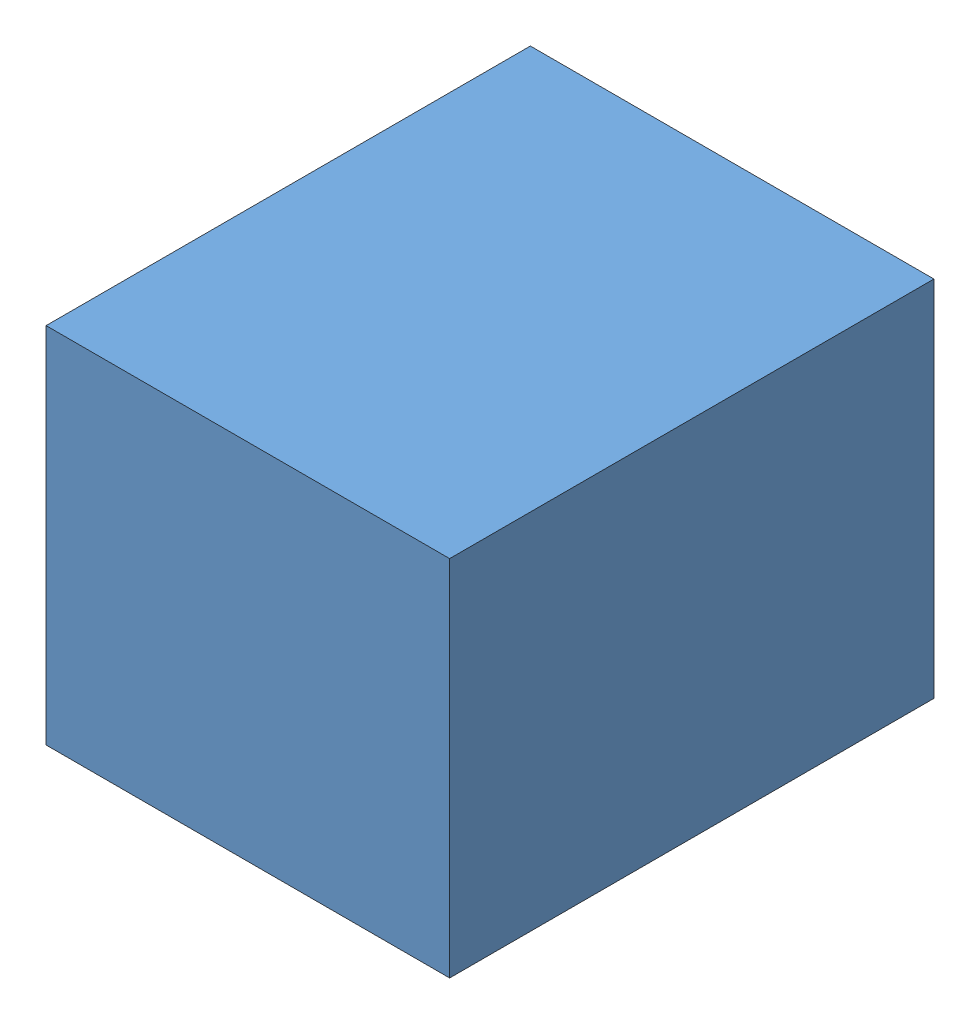
SolidWorks assembly StorageBox, configuration Default. Lengths in mm.
Overall size (500 450 600).
30 component instances, 4 part files, 20 mates.
Components (placement in the parent):
- BaseBlock-1: BaseBlock [Default] at (-55.9599 101.6948 767.1143) size (500 450 600)
- CupStorage-1: CupStorage [Default] at (882.1946 34.1249 161.3658) x (0.007369 0 0.999973) z (-0.999973 0 0.007369) size (536.8 119.37 182.42)
  - SoloCup-1: SoloCup [Default] at (135.563 292.5699 600.2365) size (96.65 119.37 96.65)
  - SoloCup-2: SoloCup [Default] at (477.5943 292.5699 516.5315) size (96.65 119.37 96.65)
  - SoloCup-3: SoloCup [Default] at (86.5797 292.5699 517.1338) size (96.65 119.37 96.65)
  - SoloCup-4: SoloCup [Default] at (429.6882 292.5699 602.3039) size (96.65 119.37 96.65)
  - SoloCup-5: SoloCup [Default] at (380.7513 292.5699 517.5282) size (96.65 119.37 96.65)
  - SoloCup-6: SoloCup [Default] at (283.0336 292.5699 517.7873) size (96.65 119.37 96.65)
  - SoloCup-7: SoloCup [Default] at (526.7308 292.5699 600.3394) size (96.65 119.37 96.65)
  - SoloCup-8: SoloCup [Default] at (234.2027 292.5699 600.9501) size (96.65 119.37 96.65)
  - SoloCup-9: SoloCup [Default] at (332.0914 292.5699 601.2137) size (96.65 119.37 96.65)
  - SoloCup-10: SoloCup [Default] at (185.2343 292.5699 517.3586) size (96.65 119.37 96.65)
  - PingPongBall-1: PingPongBall [Default] at (278.3478 273.1207 518.1565) size (38 38 38)
- CupStorage-2: CupStorage [Default] at (709.7631 34.1249 159.2975) x (0.01289 0 0.999917) z (-0.999917 0 0.01289) size (536.8 119.37 182.42)
  - SoloCup-1: SoloCup [Default] at (135.563 292.5699 600.2365) size (96.65 119.37 96.65)
  - SoloCup-2: SoloCup [Default] at (477.5943 292.5699 516.5315) size (96.65 119.37 96.65)
  - SoloCup-3: SoloCup [Default] at (86.5797 292.5699 517.1338) size (96.65 119.37 96.65)
  - SoloCup-4: SoloCup [Default] at (429.6882 292.5699 602.3039) size (96.65 119.37 96.65)
  - SoloCup-5: SoloCup [Default] at (380.7513 292.5699 517.5282) size (96.65 119.37 96.65)
  - SoloCup-6: SoloCup [Default] at (283.0336 292.5699 517.7873) size (96.65 119.37 96.65)
  - SoloCup-7: SoloCup [Default] at (526.7308 292.5699 600.3394) size (96.65 119.37 96.65)
  - SoloCup-8: SoloCup [Default] at (234.2027 292.5699 600.9501) size (96.65 119.37 96.65)
  - SoloCup-9: SoloCup [Default] at (332.0914 292.5699 601.2137) size (96.65 119.37 96.65)
  - SoloCup-10: SoloCup [Default] at (185.2343 292.5699 517.3586) size (96.65 119.37 96.65)
  - PingPongBall-1: PingPongBall [Default] at (278.3478 273.1207 518.1565) size (38 38 38)
- Battery-1: Battery [Default] at (12.3576 126.6948 331.0042) size (263 64 122)
- Battery-2: Battery [Default] at (12.3576 126.6948 465.7618) size (263 64 122)
- Battery-3: Battery [Default] at (12.3576 126.6948 605.2903) size (263 64 122)
- Battery-4: Battery [Default] at (12.3576 126.6948 733.3395) size (263 64 122)
- Battery-5: Battery [Default] at (12.3576 190.6948 540.1787) size (263 64 122)
Mates (geometry in assembly coordinates):
- Coincident11: coincident anti-aligned: plane of BaseBlock-1 through (1029.2751 326.6948 192.1143) normal (0 1 0); plane of CupStorage-1/SoloCup-1 through (282.9734 326.6948 301.3482) normal (0 -1 0)
- Coincident12: coincident anti-aligned: plane of BaseBlock-1 through (1029.2751 326.6948 192.1143) normal (0 1 0); plane of CupStorage-1/SoloCup-2 through (369.1965 326.6948 642.7535) normal (0 -1 0)
- Coincident13: coincident anti-aligned: plane of BaseBlock-1 through (1029.2751 326.6948 192.1143) normal (0 1 0); plane of CupStorage-1/SoloCup-3 through (365.7128 326.6948 251.7539) normal (0 -1 0)
- Coincident14: coincident anti-aligned: plane of BaseBlock-1 through (1029.2751 326.6948 192.1143) normal (0 1 0); plane of CupStorage-1/SoloCup-4 through (283.0734 326.6948 595.4807) normal (0 -1 0)
- Coincident15: coincident anti-aligned: plane of BaseBlock-1 through (1029.2751 326.6948 192.1143) normal (0 1 0); plane of CupStorage-1/SoloCup-5 through (367.4862 326.6948 545.9204) normal (0 -1 0)
- Coincident16: coincident anti-aligned: plane of BaseBlock-1 through (1029.2751 326.6948 192.1143) normal (0 1 0); plane of CupStorage-1/SoloCup-6 through (366.507 326.6948 448.2073) normal (0 -1 0)
- Coincident17: coincident anti-aligned: plane of BaseBlock-1 through (1029.2751 326.6948 192.1143) normal (0 1 0); plane of CupStorage-1/SoloCup-7 through (285.753 326.6948 692.5062) normal (0 -1 0)
- Coincident18: coincident anti-aligned: plane of BaseBlock-1 through (1029.2751 326.6948 192.1143) normal (0 1 0); plane of CupStorage-1/SoloCup-8 through (282.9867 326.6948 399.9905) normal (0 -1 0)
- Coincident19: coincident anti-aligned: plane of BaseBlock-1 through (1029.2751 326.6948 192.1143) normal (0 1 0); plane of CupStorage-1/SoloCup-9 through (283.4444 326.6948 497.8785) normal (0 -1 0)
- Coincident20: coincident anti-aligned: plane of BaseBlock-1 through (1029.2751 326.6948 192.1143) normal (0 1 0); plane of CupStorage-1/SoloCup-10 through (366.215 326.6948 350.4075) normal (0 -1 0)
- Coincident21: coincident anti-aligned: plane of BaseBlock-1 through (1029.2751 326.6948 192.1143) normal (0 1 0); plane of CupStorage-2/SoloCup-9 through (112.88 326.6948 499.1109) normal (0 -1 0)
- Coincident23: coincident aligned: plane of Battery-2 through (12.3576 190.6948 465.7618) normal (-1 0 0); plane of Battery-3 through (12.3576 190.6948 605.2903) normal (-1 0 0)
- Coincident24: coincident aligned: plane of Battery-2 through (12.3576 190.6948 465.7618) normal (-1 0 0); plane of Battery-5 through (12.3576 254.6948 540.1787) normal (-1 0 0)
- Coincident26: coincident aligned: plane of Battery-1 through (12.3576 190.6948 331.0042) normal (-1 0 0); plane of Battery-2 through (12.3576 190.6948 465.7618) normal (-1 0 0)
- Coincident27: coincident aligned: plane of Battery-2 through (12.3576 190.6948 465.7618) normal (-1 0 0); plane of Battery-4 through (12.3576 190.6948 733.3395) normal (-1 0 0)
- Coincident28: coincident anti-aligned: plane of BaseBlock-1 through (1029.2751 126.6948 192.1143) normal (0 1 0); plane of Battery-3 through (12.3576 126.6948 605.2903) normal (0 -1 0)
- Coincident29: coincident anti-aligned: plane of BaseBlock-1 through (1029.2751 126.6948 192.1143) normal (0 1 0); plane of Battery-2 through (12.3576 126.6948 465.7618) normal (0 -1 0)
- Coincident30: coincident anti-aligned: plane of BaseBlock-1 through (1029.2751 126.6948 192.1143) normal (0 1 0); plane of Battery-1 through (12.3576 126.6948 331.0042) normal (0 -1 0)
- Coincident31: coincident anti-aligned: plane of BaseBlock-1 through (1029.2751 126.6948 192.1143) normal (0 1 0); plane of Battery-4 through (12.3576 126.6948 733.3395) normal (0 -1 0)
- Coincident36: coincident anti-aligned: plane of Battery-2 through (12.3576 190.6948 465.7618) normal (0 1 0); plane of Battery-5 through (12.3576 190.6948 540.1787) normal (0 -1 0)
